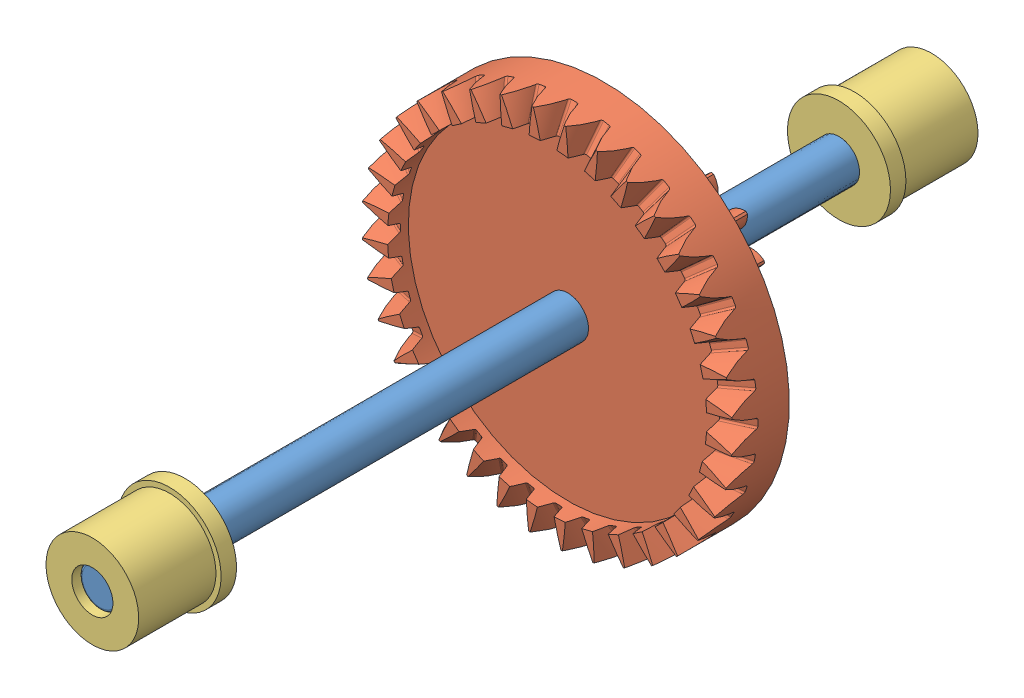
SolidWorks assembly Walking_robot_(assembled_first_axle), configuration Default. Lengths in mm.
Overall size (20.72 20.72 40.75).
4 component instances, 3 part files, 0 mates.
Components (placement in the parent):
- SHAFT 2 X 40-1: SHAFT 2 X 40 [Default] at (-15.216 11.557 0) x (-0.026375 -0.999652 0) z (0 0 1) size (2 2 40)
- pCROWN GEAR 36T X 10T R01-1: pCROWN GEAR 36T X 10T R01 [Default] at (-15.216 11.557 -3.465) x (0 0 1) z (-0.986294 -0.164995 0) size (8.17 18 18)
- ELENCO COLLAR 01-1: ELENCO COLLAR 01 [Default] at (-15.216 11.557 -15.875) x (0 0 -1) z (1 0 0) size (4.5 5 5)
- ELENCO COLLAR 01-2: ELENCO COLLAR 01 [Default] at (-15.216 11.557 15.875) x (0 0 1) z (-0.923728 -0.383049 0) size (4.5 5 5)
